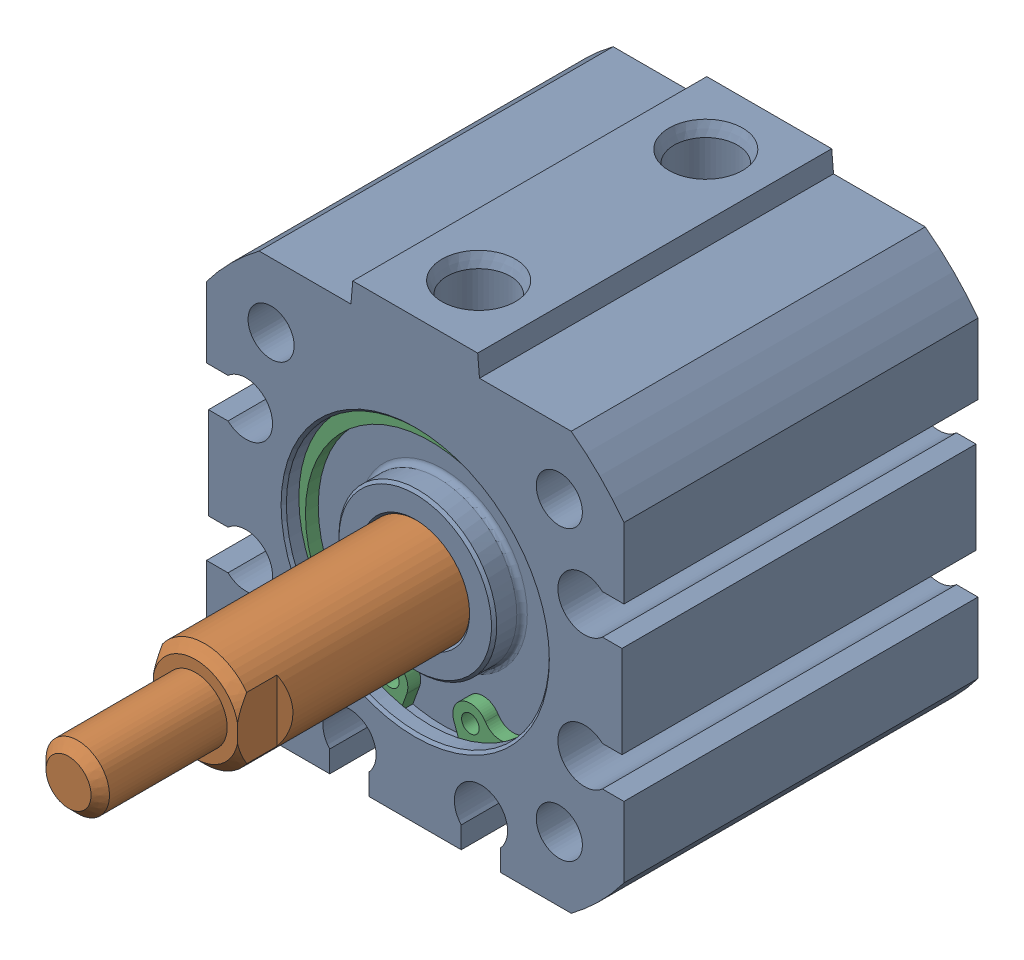
SolidWorks assembly 217-2778-001 Rev2_NCQ8A075-050M, configuration Default. Lengths in mm.
Overall size (31.75 33.34 53.29).
3 component instances, 3 part files, 0 mates.
Components (placement in the parent):
- 217-2778-NCQ8A075-050M_NCQ8 Tube_075A-1: 217-2778-NCQ8A075-050M_NCQ8 Tube_075A [Default] at origin size (31.75 33.34 26.92)
- 217-2778-NCQ8A075-050M_NCQ8 Rod_075M-1: 217-2778-NCQ8A075-050M_NCQ8 Rod_075M [Default] at (0 0 4.561) x (-1 0 0) z (0 0 1) size (18.95 18.95 35.27)
- 217-2778-NCQ8A075-050M_Snap Ring_075-1: 217-2778-NCQ8A075-050M_Snap Ring_075 [Default] at (0 0 10.362) size (21 20.74 0.97)
